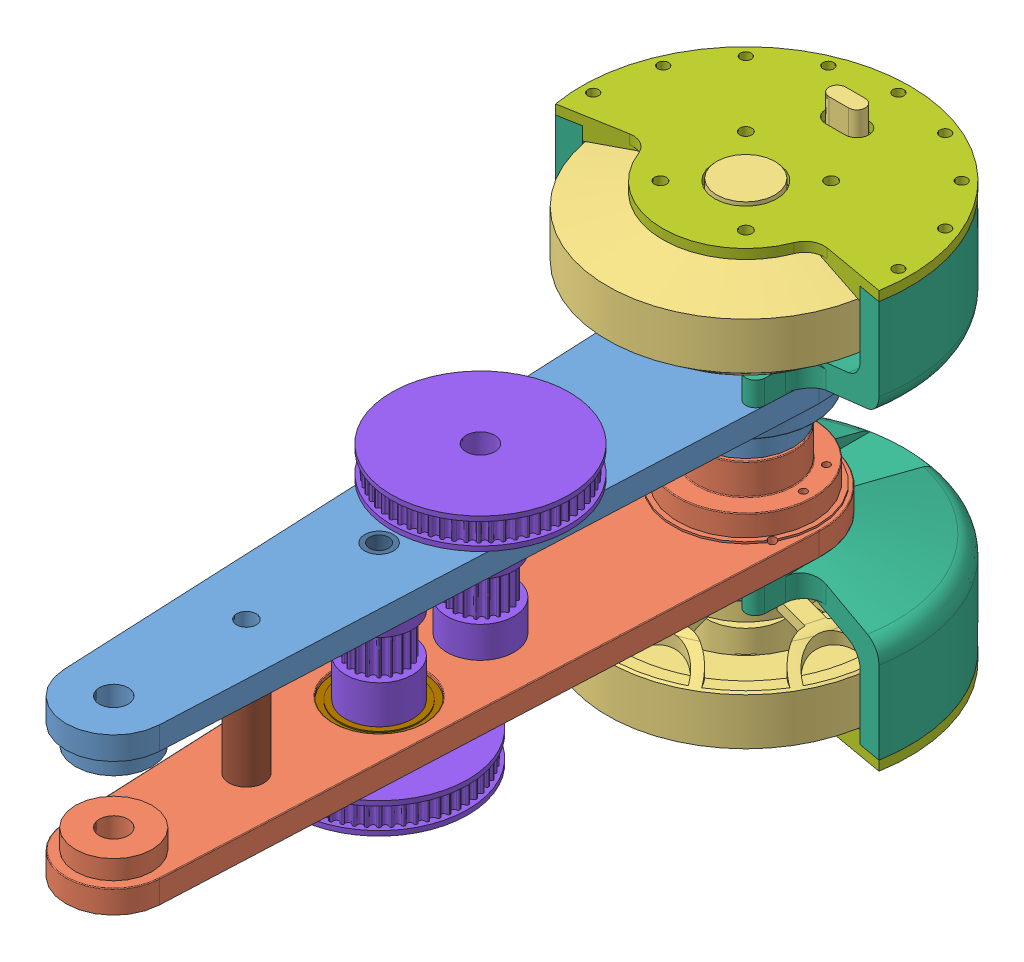
SolidWorks assembly Upper, configuration Default. Lengths in mm.
Overall size (129.63 152.13 290.11).
31 component instances, 17 part files, 28 mates.
Components (placement in the parent):
- Base-1: Base [Default] at origin size (97.08 97.08 147.72) (hidden)
  - Base Joint-1: Base Joint [Default] at origin size (76.41 40.94 91.78)
  - Bearing 45_58_7mm-1: Bearing 45_58_7mm [Default] at (0 14.1125 0) x (-0.796354 0 0.604831) z (0 1 0) size (58 58 7)
  - Bearing 45_58_7mm-2: Bearing 45_58_7mm [Default] at (0 -14.1125 0) x (-0.796354 0 0.604831) z (0 1 0) size (58 58 7)
  - Base Pulley-1: Base Pulley [Default] at (0 0 61.5165) x (0 1 0) z (1 0 0) size (97.08 44.31 97.08)
  - Bearing 45_58_7mm-3: Bearing 45_58_7mm [Default] at (0 0 78.8352) x (0.359426 0.933173 0) z (0 0 -1) size (58 58 7)
  - Bearing 45_58_7mm-4: Bearing 45_58_7mm [Default] at (0 0 97.2352) x (-0.999991 0.004136 0) z (0 0 -1) size (58 58 7)
  - Part2^Base-1: Part2^Base [Default] at origin size (83.4 83.4 31.75) (virtual)
  - Part5^Base-1: Part5^Base [Default] at origin size (47 47 2.54) (virtual)
- UpperLink Left-1: UpperLink Left [Default] at (0 22.0425 0) x (1 0 0) z (0 -1 0) size (50.8 250.69 25.4)
- UpperLink Right-1: UpperLink Right [Default] at (0 -22.0425 0) x (-1 0 0) z (0 1 0) size (50.8 250.69 25.4)
- MotorPulleyHall-1: MotorPulleyHall [Default] at (0 -65.7833 0) size (129.63 52.01 129.63)
  - 9225 160kv-1: 9225 160kv [Default] at (0 -3.93 0) x (0.707107 0 0.707107) z (-0.707107 0 0.707107) size (91.66 44.53 91.66)
  - 20 tooth htd 3mm pulley-1: 20 tooth htd 3mm pulley [Default] at (0 33.3375 0) x (0.707107 0 0.707107) z (-0.707107 0 0.707107) size (39.69 10.17 39.69)
  - AS5047D Dev Board-1: AS5047D Dev Board [Default] at (0 41.7308 0) x (-1 0 0) z (0 0 1) size (22 6.88 28.22)
  - Copy of Part1^MotorPulleyHall-1: Copy of Part1^MotorPulleyHall [Default] at (0 65.7833 0) x (-1 0 0) z (0 0 1) size (108.81 39.93 75.78) (virtual)
  - MotorMountPlate-1: MotorMountPlate [Default] at origin size (114.06 7.53 81.9)
- MotorPulleyHall-4: MotorPulleyHall [Default] at (0 65.7833 0) x (-1 0 0) z (0 0 1) size (129.63 52.01 129.63)
  - 9225 160kv-1: 9225 160kv [Default] at (0 -3.93 0) x (0.707107 0 0.707107) z (-0.707107 0 0.707107) size (91.66 44.53 91.66)
  - 20 tooth htd 3mm pulley-1: 20 tooth htd 3mm pulley [Default] at (0 33.3375 0) x (0.707107 0 0.707107) z (-0.707107 0 0.707107) size (39.69 10.17 39.69)
  - AS5047D Dev Board-1: AS5047D Dev Board [Default] at (0 41.7308 0) x (-1 0 0) z (0 0 1) size (22 6.88 28.22)
  - Copy of Part1^MotorPulleyHall-1: Copy of Part1^MotorPulleyHall [Default] at (0 65.7833 0) x (-1 0 0) z (0 0 1) size (108.81 39.93 75.78) (virtual)
  - MotorMountPlate-1: MotorMountPlate [Default] at origin size (114.06 7.53 81.9)
- 60 tooth htd 3mm pulley-3: 60 tooth htd 3mm pulley [Default] at (0 -32.4458 121.5) x (0 0 -1) z (1 0 0) size (58.88 54.36 58.88)
- 60 tooth htd 3mm pulley-1: 60 tooth htd 3mm pulley [Default] at (0 32.4458 87.917) x (0.733312 0 0.679893) z (0.679893 0 -0.733312) size (58.88 54.36 58.88)
- Bearing ,875_1,315_,25-1: Bearing ,875_1,315_,25 [Default] at (0 22.6775 87.917) x (0.963518 0 0.267643) z (-0.267643 0 0.963518) size (33.34 7.09 33.34)
- Bearing ,875_1,315_,25-2: Bearing ,875_1,315_,25 [Default] at (0 -22.6775 121.5) x (0.982251 0 0.187574) z (-0.187574 0 0.982251) size (33.34 7.09 33.34)
- bushing-1: bushing [Default] at (0 22.6775 121.5) size (9.53 6.35 9.53)
- bushing-2: bushing [Default] at (0 -22.6775 87.917) size (9.53 6.35 9.53)
- Part1^Upper-1: Part1^Upper [Default] at origin size (115.08 45.65 85.04) (hidden, virtual)
- support bracket-3: support bracket [Default] at (0 0 165.4585) size (11.56 36.45 11.56)
Mates (geometry in assembly coordinates):
- Coincident1: coincident aligned: line of MotorPulleyHall-1 through (57.2118 0 -21.452) axis (0 0 -1)
- Coincident3: coincident anti-aligned: plane of UpperLink-1 through (0 0 205.4835) normal (0 -1 0)
- Coincident4: coincident: point of UpperLink Right-1
- Coincident6: coincident anti-aligned: plane of UpperLink Right-1 through (0 -22.0425 0) normal (-1 0 0)
- Coincident7: coincident aligned: plane of MotorPulleyHall-1 through (0 -65.7833 0) normal (1 0 0)
- Coincident8: coincident aligned: plane of UpperLink Right-1 through (0 -25.8525 209.417) normal (0 -1 0); plane of MotorPulleyHall-1/AS5047D Dev Board-1 through (0 -25.8525 0) normal (0 -1 0)
- Concentric1: concentric: cylinder of UpperLink Right-1 through (0 -25.8525 87.917) axis (0 1 0) radius 4.7625; point of 60 tooth htd 3mm pulley-1
- Coincident10: coincident aligned: plane of MotorPulleyHall-1/15 tooth htd 3mm pulley-1 through (0 -32.4458 0) normal (0 1 0); plane of 60 tooth htd 3mm pulley-3 through (0 -32.4458 121.5) normal (0 1 0)
- Coincident14: coincident aligned: plane of MotorPulleyHall-1/9225 160kv-1 through (-3.25 -76.0633 -30.83) normal (0 0 1); plane of MotorPulleyHall-4/9225 160kv-1 through (3.25 76.0633 -30.83) normal (0 0 1)
- Coincident15: coincident aligned: plane of 60 tooth htd 3mm pulley-1 through (0 32.4458 87.917) normal (0 -1 0); plane of MotorPulleyHall-4/15 tooth htd 3mm pulley-1 through (0 32.4458 0) normal (0 -1 0)
- Coincident16: coincident anti-aligned: plane of Base-1/Bearing-2 through (0 -17.6125 0) normal (0 -1 0); plane of UpperLink Right-1 through (0 -17.6125 0) normal (0 1 0)
- Symmetric1: symmetric aligned: plane of UpperLink Right-1 through (0 -18.2325 209.417) normal (0 1 0); plane of UpperLink Left-1 through (0 18.2325 209.417) normal (0 -1 0)
- Concentric2: concentric anti-aligned: cylinder of UpperLink Right-1 through (0 -10.6125 0) axis (0 -1 0) radius 22.5; cylinder of UpperLink Left-1 through (0 10.6125 0) axis (0 1 0) radius 22.5
- Coincident17: coincident aligned: plane of UpperLink Left-1 through (0 22.0425 0) normal (1 0 0)
- Concentric3: concentric anti-aligned: cylinder of MotorPulleyHall-1/9225 160kv-1 through (0 -31.5333 0) axis (0 1 0) radius 45.83; cylinder of MotorPulleyHall-4/9225 160kv-1 through (0 31.5333 0) axis (0 -1 0) radius 45.83
- Symmetric2: symmetric aligned: plane of MotorPulleyHall-1/9225 160kv-1 through (0 -69.7133 0) normal (0 -1 0); plane of MotorPulleyHall-4/9225 160kv-1 through (0 69.7133 0) normal (0 1 0)
- Concentric4: concentric aligned: cylinder of UpperLink Left-1 through (0 25.8525 87.917) axis (0 -1 0) radius 16.6687; cylinder of Bearing ,875_1,315_,25-1 through (0 25.8525 87.917) axis (0 -1 0) radius 16.6687
- Concentric5: concentric anti-aligned: cylinder of UpperLink Right-1 through (0 -25.8525 121.5) axis (0 1 0) radius 16.6687; cylinder of Bearing ,875_1,315_,25-2 through (0 -19.5025 121.5) axis (0 -1 0) radius 16.6687
- Symmetric3: symmetric anti-aligned: plane of Bearing ,875_1,315_,25-1 through (0 22.6775 87.917) normal (0 1 0); plane of Bearing ,875_1,315_,25-2 through (0 -22.6775 121.5) normal (0 1 0)
- Coincident18: coincident aligned: plane of UpperLink Left-1 through (0 25.8525 209.417) normal (0 1 0); plane of Bearing ,875_1,315_,25-1 through (0 25.8525 87.917) normal (0 1 0)
- Concentric6: concentric: point of 60 tooth htd 3mm pulley-3; cylinder of Bearing ,875_1,315_,25-2 through (0 -19.5025 121.5) axis (0 -1 0) radius 11.1125
- Concentric7: concentric anti-aligned: cylinder of UpperLink Left-1 through (0 25.8525 121.5) axis (0 -1 0) radius 4.7625; cylinder of bushing-1 through (0 25.8525 121.5) axis (0 1 0) radius 4.7625
- Coincident20: coincident aligned: plane of UpperLink Left-1 through (0 25.8525 209.417) normal (0 1 0); plane of bushing-1 through (-4.7625 25.8525 121.5) normal (0 1 0)
- Concentric8: concentric aligned: cylinder of UpperLink Right-1 through (0 -25.8525 87.917) axis (0 1 0) radius 4.7625; cylinder of bushing-2 through (0 -19.5025 87.917) axis (0 1 0) radius 4.7625
- Coincident21: coincident aligned: plane of UpperLink Right-1 through (0 -25.8525 209.417) normal (0 -1 0); plane of bushing-2 through (-4.7625 -25.8525 87.917) normal (0 -1 0)
- Coincident22: coincident aligned: plane of 60 tooth htd 3mm pulley-3 through (0 -32.4458 121.5) normal (1 0 0)
- Concentric12: concentric aligned: cylinder of UpperLink Left-1 through (0 25.8525 165.4585) axis (0 -1 0) radius 3.2385; cylinder of support bracket-3 through (0 18.2245 165.4585) axis (0 -1 0) radius 5.7785
- Symmetric4: symmetric aligned: plane of UpperLink Left-1 through (0 18.2325 209.417) normal (0 -1 0); plane of UpperLink Right-1 through (0 -18.2325 209.417) normal (0 1 0); plane of support bracket-3 through (0 0 165.4585) normal (0 1 0)
